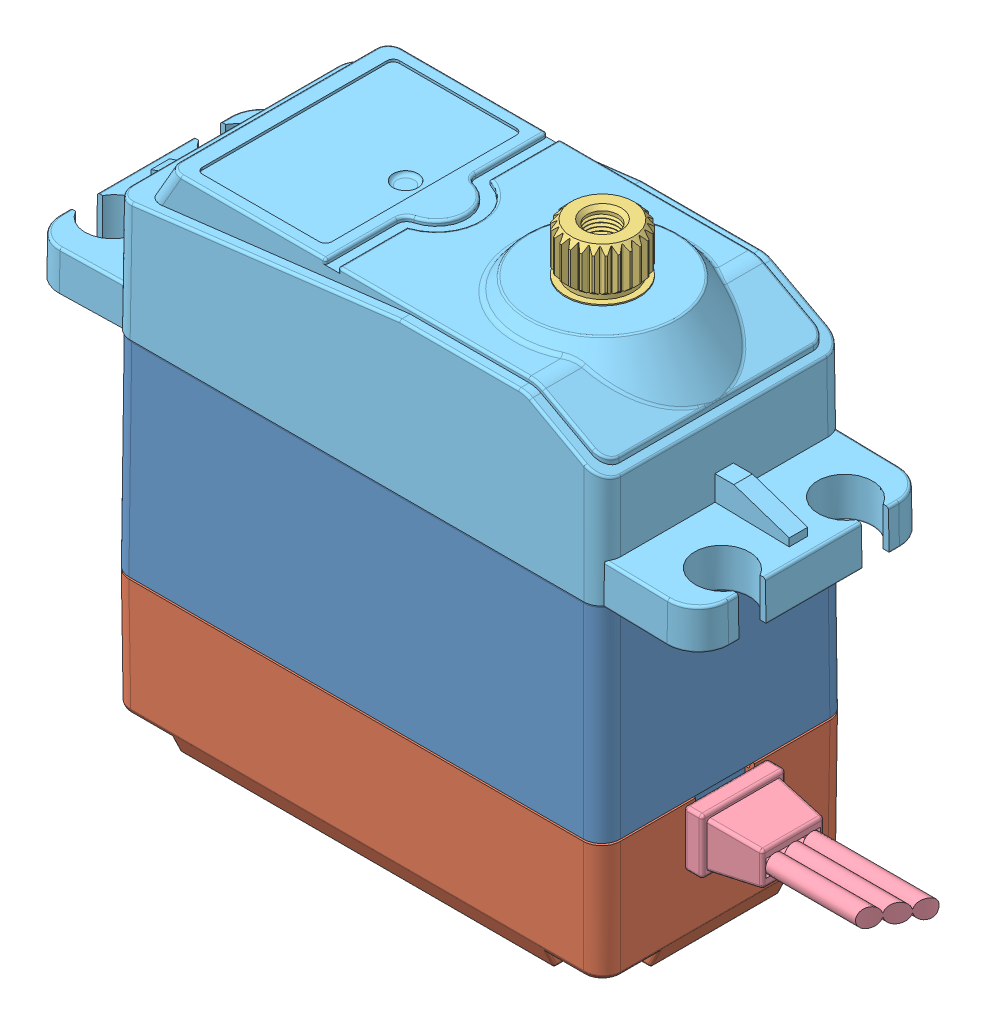
SolidWorks assembly DS3218, configuration Default. Lengths in mm.
Overall size (62.26 45.55 20.04).
5 component instances, 5 part files, 0 mates.
Components (placement in the parent):
- ZK-1: ZK [Default] at origin size (39.93 19 20.03)
- DG-SZ-1: DG-SZ [Default] at origin size (39.94 11.01 20.04)
- GE-1: GE [Default] at (10 10.9 0) x (1 0 0) z (0 -1 0) size (17.3 17.3 15.8)
- XIANTAO-1: XIANTAO [Default] at (18.2007 -11.45 -0.1) size (18.42 4.5 6.8)
- SG-JIANRONG-MG996-1: SG-JIANRONG-MG996 [Default] at origin size (54.38 13.91 19.9)
